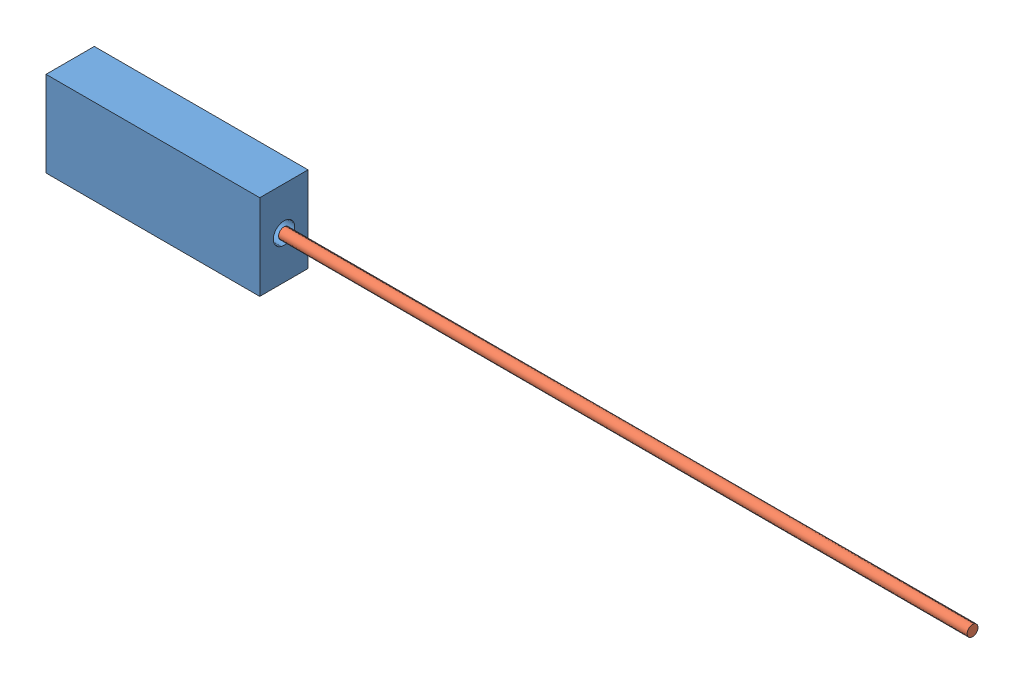
SolidWorks assembly Harness_28-CABLE_REALOP_ONE_ASSEMBLY, configuration AnnotateFlattenedRoute1 - Default. Lengths in mm.
Overall size (42.21 4 2.26).
3 component instances, 3 part files, 1 mates.
Components (placement in the parent):
- 1_PIN-1: 1_PIN [Default] at (-10 2 -1.125) x (0 0 1) z (1 0 0) size (2.26 4 20)
- Cable^Harness_28-CABLE_REALOP_ONE_ASSEMBLY-1: Cable^Harness_28-CABLE_REALOP_ONE_ASSEMBLY [Default] at origin size (12.71 26.96 29.34) (suppressed, hidden, virtual)
- Flattened_Cable^Harness_28-CABLE_REALOP_ONE_ASSEMBLY-1: Flattened_Cable^Harness_28-CABLE_REALOP_ONE_ASSEMBLY [Default] at origin (virtual)
Mates (geometry in assembly coordinates):
- Coincident1031: coincident anti-aligned: plane of X_AND_Y_SOLAR_ARRAYS-2 through (89.5177 -21.2025 126.3251) normal (-1 0 0); plane of 1_PIN-1 through (89.5177 44.2025 258.3381) normal (1 0 0)
